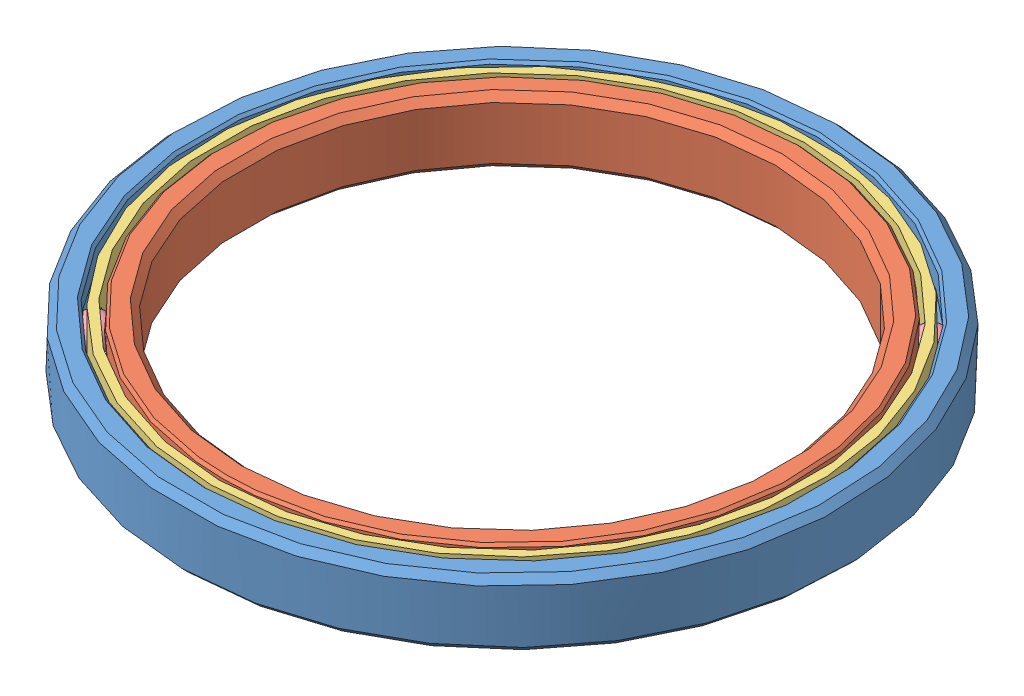
SolidWorks assembly SW3dPS partNO- -KA020AR0, configuration KA020CP0. Lengths in mm.
Overall size (63.5 6.35 63.5).
31 component instances, 4 part files, 6 mates.
Components (placement in the parent):
- SW3dPS-KA - Radial Contact_KA OUTER CATALOG-1: SW3dPS-KA - Radial Contact_KA OUTER CATALOG [KA020002] at origin size (63.5 6.35 63.5)
- SW3dPS-KA - Radial Contact_KA INNER CATALOG-1: SW3dPS-KA - Radial Contact_KA INNER CATALOG [KA020003] at origin size (55.52 6.35 55.52)
- SW3dPS-KA - Radial Contact_KA SEPARATOR SAMPLE-1: SW3dPS-KA - Radial Contact_KA SEPARATOR SAMPLE [KA020] at origin size (60.31 5.28 60.41)
  - SW3dPS-KA - Radial Contact_KA SEPARATOR SAMPLE-1: SW3dPS-KA - Radial Contact_KA SEPARATOR SAMPLE [02510020] at origin size (57.94 5.28 57.94)
  - SW3dPS-KA - Radial Contact_KA BALL-1: SW3dPS-KA - Radial Contact_KA BALL [KA020] at origin size (3.17 3.17 3.17)
  - SW3dPS-KA - Radial Contact_KA BALL-2: SW3dPS-KA - Radial Contact_KA BALL [KA020] x (0.973045 0 0.230616) z (-0.230616 0 0.973045) size (3.17 3.17 3.17)
  - SW3dPS-KA - Radial Contact_KA BALL-3: SW3dPS-KA - Radial Contact_KA BALL [KA020] x (0.893633 0 0.448799) z (-0.448799 0 0.893633) size (3.17 3.17 3.17)
  - SW3dPS-KA - Radial Contact_KA BALL-4: SW3dPS-KA - Radial Contact_KA BALL [KA020] x (0.766044 0 0.642788) z (-0.642788 0 0.766044) size (3.17 3.17 3.17)
  - SW3dPS-KA - Radial Contact_KA BALL-5: SW3dPS-KA - Radial Contact_KA BALL [KA020] x (0.597159 0 0.802123) z (-0.802123 0 0.597159) size (3.17 3.17 3.17)
  - SW3dPS-KA - Radial Contact_KA BALL-6: SW3dPS-KA - Radial Contact_KA BALL [KA020] x (0.39608 0 0.918216) z (-0.918216 0 0.39608) size (3.17 3.17 3.17)
  - SW3dPS-KA - Radial Contact_KA BALL-7: SW3dPS-KA - Radial Contact_KA BALL [KA020] x (0.173648 0 0.984808) z (-0.984808 0 0.173648) size (3.17 3.17 3.17)
  - SW3dPS-KA - Radial Contact_KA BALL-8: SW3dPS-KA - Radial Contact_KA BALL [KA020] x (-0.058145 0 0.998308) z (-0.998308 0 -0.058145) size (3.17 3.17 3.17)
  - SW3dPS-KA - Radial Contact_KA BALL-9: SW3dPS-KA - Radial Contact_KA BALL [KA020] x (-0.286803 0 0.95799) z (-0.95799 0 -0.286803) size (3.17 3.17 3.17)
  - SW3dPS-KA - Radial Contact_KA BALL-10: SW3dPS-KA - Radial Contact_KA BALL [KA020] x (-0.5 0 0.866025) z (-0.866025 0 -0.5) size (3.17 3.17 3.17)
  - SW3dPS-KA - Radial Contact_KA BALL-11: SW3dPS-KA - Radial Contact_KA BALL [KA020] x (-0.686242 0 0.727374) z (-0.727374 0 -0.686242) size (3.17 3.17 3.17)
  - SW3dPS-KA - Radial Contact_KA BALL-12: SW3dPS-KA - Radial Contact_KA BALL [KA020] x (-0.835488 0 0.549509) z (-0.549509 0 -0.835488) size (3.17 3.17 3.17)
  - SW3dPS-KA - Radial Contact_KA BALL-13: SW3dPS-KA - Radial Contact_KA BALL [KA020] x (-0.939693 0 0.34202) z (-0.34202 0 -0.939693) size (3.17 3.17 3.17)
  - SW3dPS-KA - Radial Contact_KA BALL-14: SW3dPS-KA - Radial Contact_KA BALL [KA020] x (-0.993238 0 0.116093) z (-0.116093 0 -0.993238) size (3.17 3.17 3.17)
  - SW3dPS-KA - Radial Contact_KA BALL-15: SW3dPS-KA - Radial Contact_KA BALL [KA020] x (-0.993238 0 -0.116093) z (0.116093 0 -0.993238) size (3.17 3.17 3.17)
  - SW3dPS-KA - Radial Contact_KA BALL-16: SW3dPS-KA - Radial Contact_KA BALL [KA020] x (-0.939693 0 -0.34202) z (0.34202 0 -0.939693) size (3.17 3.17 3.17)
  - SW3dPS-KA - Radial Contact_KA BALL-17: SW3dPS-KA - Radial Contact_KA BALL [KA020] x (-0.835488 0 -0.549509) z (0.549509 0 -0.835488) size (3.17 3.17 3.17)
  - SW3dPS-KA - Radial Contact_KA BALL-18: SW3dPS-KA - Radial Contact_KA BALL [KA020] x (-0.686242 0 -0.727374) z (0.727374 0 -0.686242) size (3.17 3.17 3.17)
  - SW3dPS-KA - Radial Contact_KA BALL-19: SW3dPS-KA - Radial Contact_KA BALL [KA020] x (-0.5 0 -0.866025) z (0.866025 0 -0.5) size (3.17 3.17 3.17)
  - SW3dPS-KA - Radial Contact_KA BALL-20: SW3dPS-KA - Radial Contact_KA BALL [KA020] x (-0.286803 0 -0.95799) z (0.95799 0 -0.286803) size (3.17 3.17 3.17)
  - SW3dPS-KA - Radial Contact_KA BALL-21: SW3dPS-KA - Radial Contact_KA BALL [KA020] x (-0.058145 0 -0.998308) z (0.998308 0 -0.058145) size (3.17 3.17 3.17)
  - SW3dPS-KA - Radial Contact_KA BALL-22: SW3dPS-KA - Radial Contact_KA BALL [KA020] x (0.173648 0 -0.984808) z (0.984808 0 0.173648) size (3.17 3.17 3.17)
  - SW3dPS-KA - Radial Contact_KA BALL-23: SW3dPS-KA - Radial Contact_KA BALL [KA020] x (0.39608 0 -0.918216) z (0.918216 0 0.39608) size (3.17 3.17 3.17)
  - SW3dPS-KA - Radial Contact_KA BALL-24: SW3dPS-KA - Radial Contact_KA BALL [KA020] x (0.597159 0 -0.802123) z (0.802123 0 0.597159) size (3.17 3.17 3.17)
  - SW3dPS-KA - Radial Contact_KA BALL-25: SW3dPS-KA - Radial Contact_KA BALL [KA020] x (0.766044 0 -0.642788) z (0.642788 0 0.766044) size (3.17 3.17 3.17)
  - SW3dPS-KA - Radial Contact_KA BALL-26: SW3dPS-KA - Radial Contact_KA BALL [KA020] x (0.893633 0 -0.448799) z (0.448799 0 0.893633) size (3.17 3.17 3.17)
  - SW3dPS-KA - Radial Contact_KA BALL-27: SW3dPS-KA - Radial Contact_KA BALL [KA020] x (0.973045 0 -0.230616) z (0.230616 0 0.973045) size (3.17 3.17 3.17)
Mates (geometry in assembly coordinates):
- Concentric1: concentric anti-aligned: cylinder of SW3dPS-KA - Radial Contact_KA OUTER CATALOG-1; cylinder of SW3dPS-KA - Radial Contact_KA INNER CATALOG-1
- Coincident1: coincident: point of SW3dPS-KA - Radial Contact_KA INNER CATALOG-1; point of assembly
- Coincident2: coincident aligned: plane of SW3dPS-KA - Radial Contact_KA INNER CATALOG-1; plane of assembly
- Concentric2: concentric anti-aligned: cylinder of SW3dPS-KA - Radial Contact_KA OUTER CATALOG-1; cylinder of ?
- Coincident4: coincident: point of ?; point of assembly
- Coincident5: coincident aligned: plane of ?; plane of assembly
